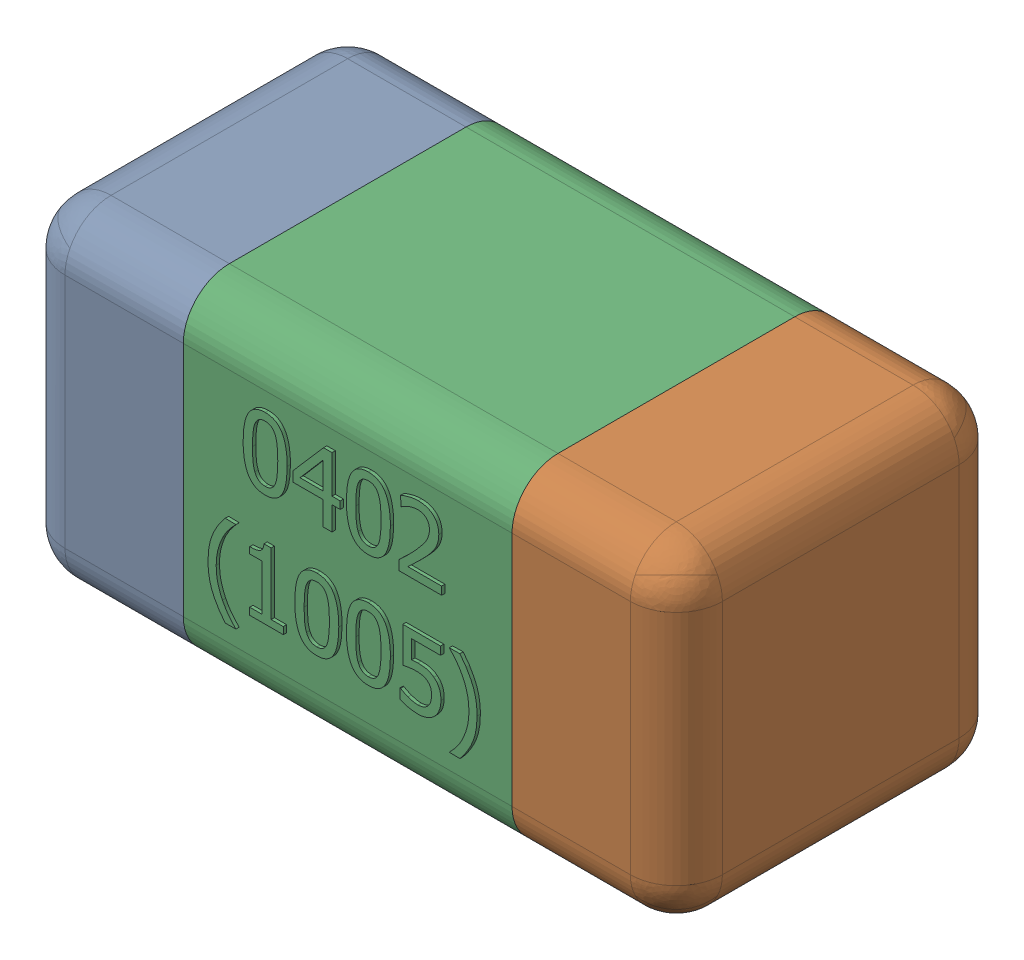
SolidWorks assembly C7, configuration Standard. Lengths in mm.
Overall size (1.01 0.51 0.51).
4 component instances, 3 part files, 0 mates.
Components (placement in the parent):
- C7-subassembly-1-1: C7-subassembly-1 [Standard] at (5.9001 -1.1 0) x (1 0 0) z (0 0 1) size (1.01 0.51 0.51)
  - User Library-0402_Cap-1: User Library-0402_Cap [Standard] at origin size (0.26 0.51 0.51)
  - User Library-0402_Cap-1-1: User Library-0402_Cap-1 [Standard] at origin size (0.26 0.5 0.51)
  - User Library-0402_Cap-2-1: User Library-0402_Cap-2 [Standard] at origin size (0.5 0.5 0.51)
